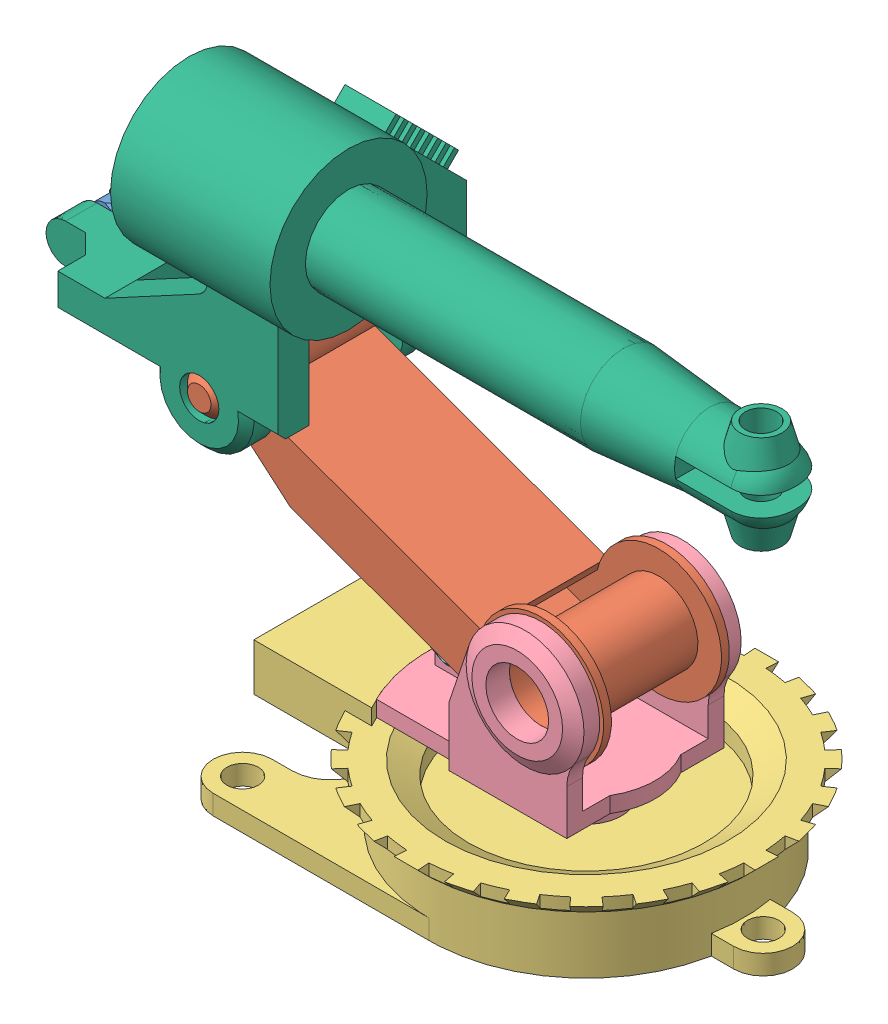
SolidWorks assembly notrealmirror, configuration Default. Lengths in mm.
Overall size (195.82 140.34 92).
6 component instances, 6 part files, 14 mates.
Components (placement in the parent):
- ActPiston-1: ActPiston [Default] at (-68.029 50.2402 0) x (0 0 1) z (-0.484661 -0.874702 0) size (8 84.03 8)
- MainArm-1: MainArm [Default] at (4.3934 45.6066 16) x (-0.34202 -0.939693 0) z (0.939693 -0.34202 0) size (32 48 105)
- PlateBase(New Design)-1: PlateBase(New Design) [Default] at origin size (117.14 24 92)
- Rotating Base-1: Rotating Base [Default] at (0 20 0) size (59.39 48.61 44)
- ActHousing-1: ActHousing [Default] at (-36.7482 32.908 0) x (0 0 1) z (-0.484661 -0.874702 0) size (10 60.02 10)
- SubArmMirror-2: SubArmMirror [Default] at (-74.5408 74.3363 -24) x (1 0 0) z (0 -1 0) size (195.38 60.51 78)
Mates (geometry in assembly coordinates):
- Concentric1: concentric aligned: cylinder of PlateBase(New Design)-1 through (0 12 0) axis (0 1 0) radius 6; cylinder of Rotating Base-1 through (0 12 0) axis (0 1 0) radius 6
- Coincident1: coincident anti-aligned: plane of PlateBase(New Design)-1 through (0 12 0) normal (0 1 0); plane of Rotating Base-1 through (0 12 0) normal (0 -1 0)
- Coincident3: coordinate: point of PlateBase(New Design)-1
- Concentric2: concentric aligned: cylinder of MainArm-1 through (4.3934 45.6066 -16) axis (0 0 1) radius 8; cylinder of Rotating Base-1 through (4.3934 45.6066 -73.2147) axis (0 0 1) radius 8
- Coincident4: coincident anti-aligned: plane of MainArm-1 through (4.3934 45.6066 -16) normal (0 0 -1); plane of Rotating Base-1 through (19.3934 62.7339 -16) normal (0 0 1)
- Concentric5: concentric aligned: cylinder of Rotating Base-1 through (-31.5 30 -7.5) axis (0 0 1) radius 2.5; cylinder of ActHousing-1 through (-31.5 30 -5) axis (0 0 1) radius 2.5
- Coincident6: coincident anti-aligned: plane of Rotating Base-1 through (-36 34 -2.5) normal (0 0 -1); plane of ActHousing-1 through (-29.8354 24.345 -2.5) normal (0 0 1)
- Concentric7: concentric aligned: cylinder of ActPiston-1 through (-116.2998 71.9625 0) axis (0.896269 -0.443511 0) radius 4; cylinder of ActHousing-1 through (-85.2761 56.6107 0) axis (0.896269 -0.443511 0) radius 4
- Parallel1: parallel aligned: plane of PlateBase(New Design)-1 through (-64.641 12 20) normal (0 0 1); plane of Rotating Base-1 through (0 24 17.5) normal (0 0 1)
- Angle1: planar angle = 0.349066 rad anti-aligned: plane of MainArm-1 through (-7.6737 35.1002 -16) normal (-0.34202 -0.939693 0); plane of Rotating Base-1 through (19.3934 24 -16) normal (0 1 0)
- Concentric8: concentric anti-aligned: cylinder of MainArm-1 through (-74.5408 74.3363 -24) axis (0 0 1) radius 5; cylinder of SubArmMirror-2 through (-30.8357 74.3363 33.3661) axis (0 0 -1) radius 5
- Coincident10: coincident anti-aligned: plane of MainArm-1 through (4.3934 45.6066 -16) normal (0 0 -1); plane of SubArmMirror-2 through (-52.8152 54.9248 -6.6339) normal (0 0 1)
- Concentric9: concentric anti-aligned: cylinder of ActPiston-1 through (-120.8115 74.195 -2) axis (0 0 1) radius 2.5; cylinder of SubArmMirror-2 through (-77.1064 74.195 20.4372) axis (0 0 -1) radius 2.5
- Parallel4: parallel aligned: plane of PlateBase(New Design)-1 through (0 24 0) normal (0 1 0); plane of SubArmMirror-2 through (-110.5408 84.3363 -24) normal (0 1 0)
